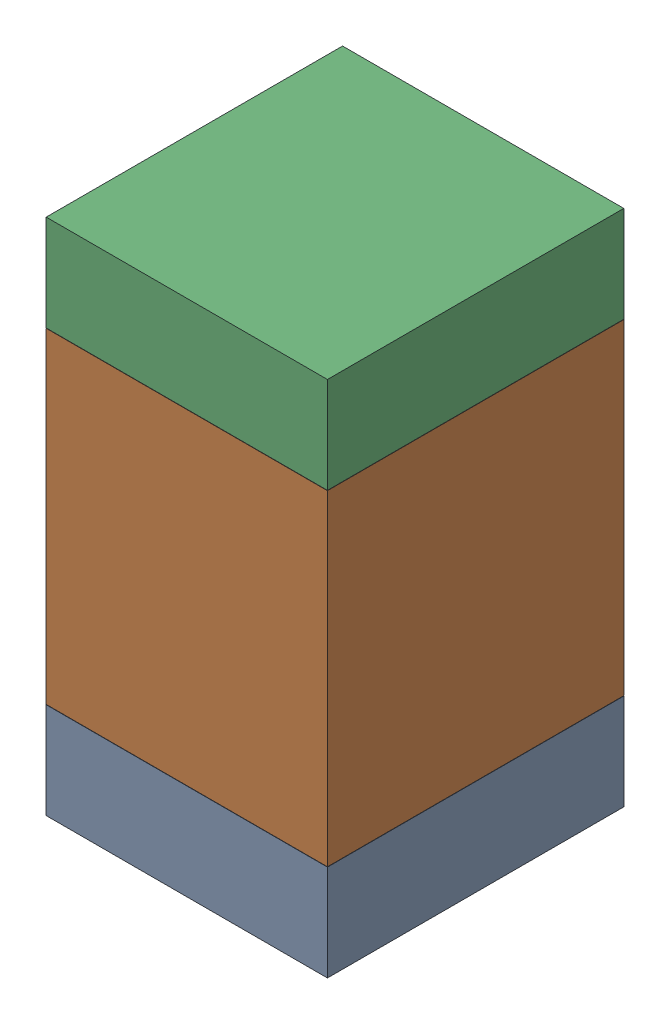
SolidWorks assembly C9, configuration Default. Lengths in mm.
Overall size (0.95 1.75 1).
6 component instances, 2 part files, 0 mates.
Components (placement in the parent):
- 6575495072-1: 6575495072 [Default] at (3.048 25.7035 0) size (0.95 0.32 1)
  - Extruded_6-1: Extruded_6 [Default] at origin size (0.95 0.32 1)
- 6575494912-1: 6575494912 [Default] at (3.048 26.416 0) size (0.95 1.1 1)
  - Extruded_7-1: Extruded_7 [Default] at origin size (0.95 1.1 1)
- 6575495072-2: 6575495072 [Default] at (3.048 27.1285 0) size (0.95 0.32 1)
  - Extruded_6-1: Extruded_6 [Default] at origin size (0.95 0.32 1)
